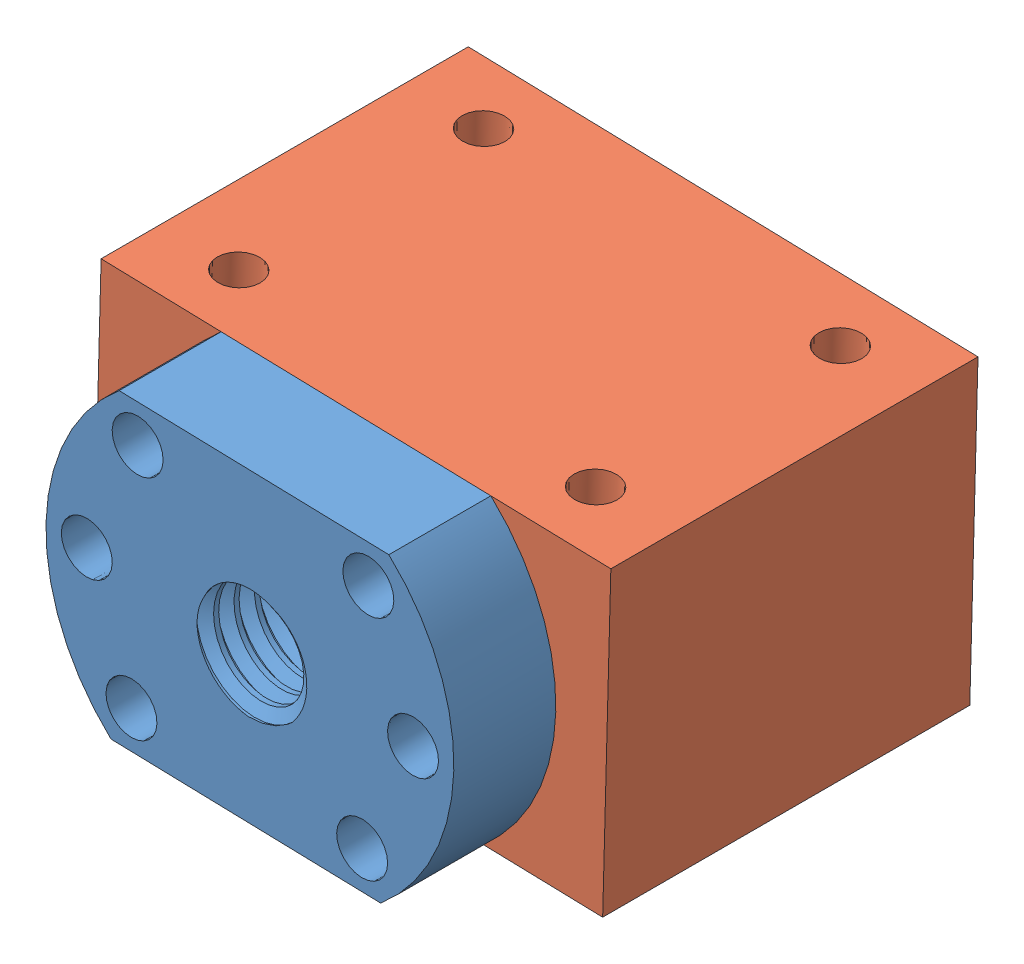
SolidWorks assembly Assem1, configuration Default. Lengths in mm.
Overall size (50.79 31.33 46.87).
2 component instances, 2 part files, 2 mates.
Components (placement in the parent):
- nut-1: nut [Default] at (7.5358 24.4303 13.1314) x (0.026783 0.999641 0) z (0 0 1) size (30 40 41.74)
- nut seat-1: nut seat [Default] at (7.5358 24.4303 -22.8686) x (0.999641 -0.026783 0) z (0 0 1) size (50 30 36)
Mates (geometry in assembly coordinates):
- Concentric1: concentric: cylinder of nut-1 through (7.5358 24.4303 3.2256) axis (0 0 1) radius 11; cylinder of nut seat-1 through (7.5358 24.4303 13.1314) axis (0 0 -1) radius 11
- Coincident2: coincident aligned: line of nut-1 through (-6.09 9.79 13.1314) axis (0.999641 -0.026783 0); line of nut seat-1 through (-17.857 10.1052 13.1314) axis (0.999641 -0.026783 0)
